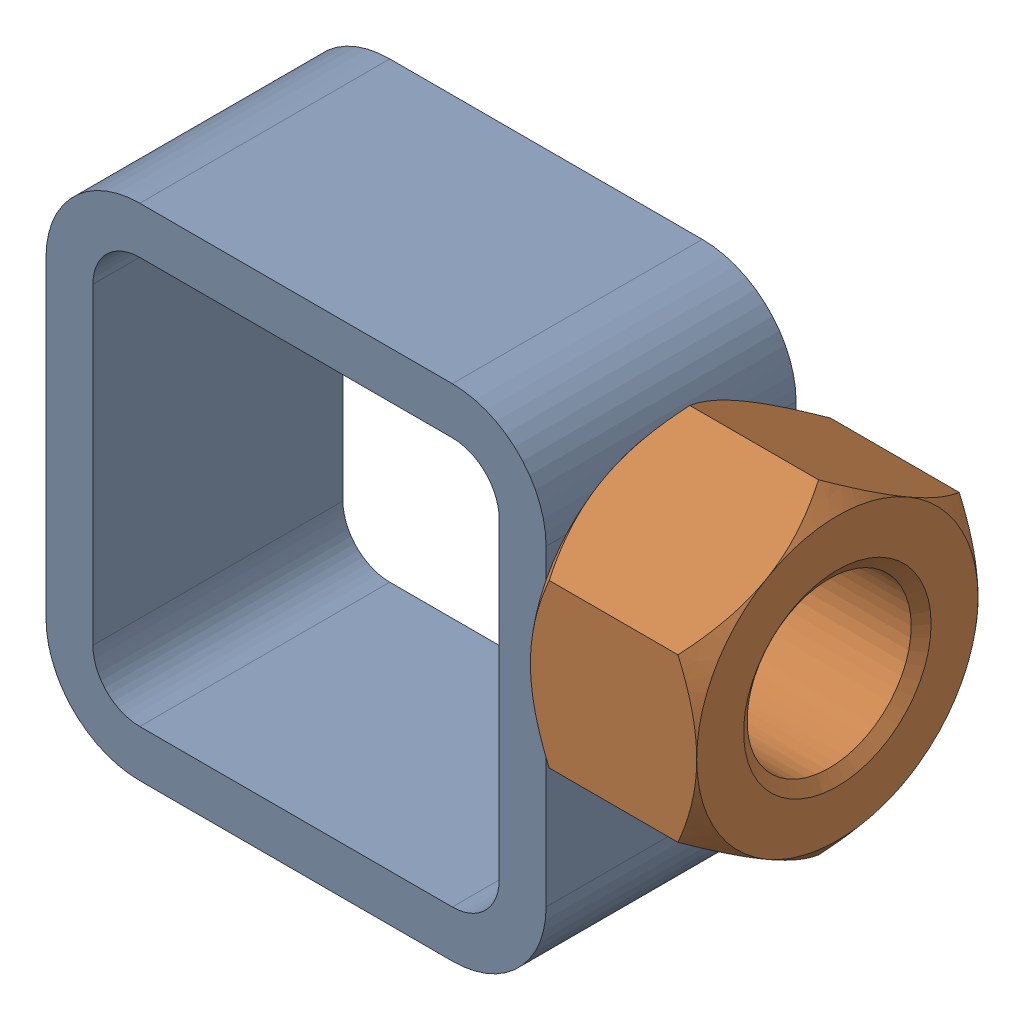
SolidWorks assembly 01-005-00-0-9, configuration Default. Lengths in mm.
Overall size (67.69 50.8 28.57).
2 component instances, 2 part files, 0 mates.
Components (placement in the parent):
- tube square_ai(PreviewCfg)-1: tube square_ai(PreviewCfg) [Default] at origin size (50.8 50.8 25.4)
- hex nut_ai(HNUT 0.7500-10-D-C)-1: hex nut_ai(HNUT 0.7500-10-D-C) [Default] at (67.691 31.75 0) x (0 0 -1) z (1 0 0) size (28.57 33 16.89)
